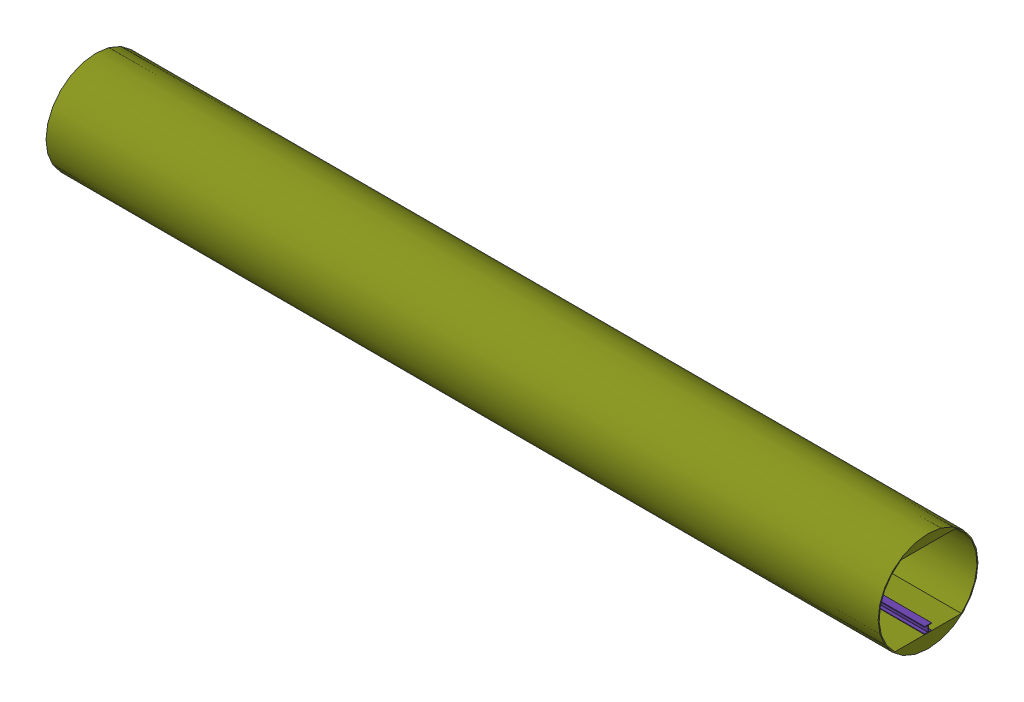
SolidWorks assembly full_vehicle_on_track, configuration Default. Lengths in mm.
Overall size (15240 1828.8 1828.8).
31 component instances, 17 part files, 5 mates.
Components (placement in the parent):
- full_vehicle-1: full_vehicle [Default] at (2562.0432 -2358.5258 -4406.3331) size (6096.03 1166.77 1555.25)
  - sledFrame_003_rw-1: sledFrame_003_rw [Default] at (-4891.4665 1903.7696 4433.3238) size (5588 50.8 1016)
  - drive_assembly-1: drive_assembly [Default] at (-3341.0425 1915.3862 4244.1915) x (0 0 1) z (-1 0 0) size (346.08 495.3 1111.25)
    - motor-1: motor [Default] at (4.9823 194.7584 300.6208) size (114.3 330.2 254)
    - drive_wheel-1: drive_wheel [Default] at (189.1323 143.9584 -16.8792) x (0 0 -1) z (1 0 0) size (304.8 304.8 101.6)
    - vertical_stability-1: vertical_stability [Default] at (189.1323 -124.9768 -16.8792) size (165.1 348.85 530.75)
    - drive_wheel-2: drive_wheel [Default] at (189.1323 143.9584 618.1208) x (0 0 1) z (-1 0 0) size (304.8 304.8 101.6)
    - vertical_stability-2: vertical_stability [Default] at (189.1323 -124.9768 618.1208) x (-1 0 0) z (0 0 -1) size (165.1 348.85 530.75)
    - Part1^drive_assembly-1: Part1^drive_assembly [Default] at (84.3573 143.9584 -16.8792) size (12.7 192.09 339.73) (virtual)
    - Part1^drive_assembly-2: Part1^drive_assembly [Default] at (281.2073 143.9584 -16.8792) size (12.7 192.09 339.73) (virtual)
    - Part1^drive_assembly-3: Part1^drive_assembly [Default] at (84.3573 143.9584 618.1208) size (12.7 192.09 339.73) (virtual)
    - Part1^drive_assembly-4: Part1^drive_assembly [Default] at (281.2073 143.9584 618.1208) size (12.7 192.09 339.73) (virtual)
  - battery_pack-1: battery_pack [Default] at (-3018.7283 2021.2446 4823.2138) x (0 0 -1) z (1 0 0) size (134.62 152.4 1325.88)
  - battery_pack-2: battery_pack [Default] at (-3018.7283 2021.2446 4043.4338) x (0 0 1) z (-1 0 0) size (134.62 152.4 1325.88)
  - Body_006_rw-1: Body_006_rw [Default] at (-5653.4665 1954.5696 4433.3238) x (1 0 0.000021) z (-0.000021 0 1) size (6096 981.34 1555.12)
  - radiator-1: radiator [Default] at (-3872.1683 2287.9446 3998.3488) x (-1 0 0) z (0 0 1) size (381 685.8 44.45)
  - horizontal_stability-1: horizontal_stability [Default] at (-2876.2243 1919.6446 4433.3238) x (0 0 -1) z (1 0 0) size (307.09 115.06 127)
  - horizontal_stability-2: horizontal_stability [Default] at (-4311.8611 1919.6446 4433.3238) x (0 0 -1) z (1 0 0) size (307.09 115.06 127)
  - friction_brake-1: friction_brake [Default] at (-4777.1665 1901.7122 4404.7488) x (0 0 -1) z (1 0 0) size (107.95 142.42 127)
  - friction_brake-2: friction_brake [Default] at (-4777.1665 1901.7122 4461.8988) x (0 0 1) z (-1 0 0) size (107.95 142.42 127)
  - friction_brake-3: friction_brake [Default] at (-2451.0383 1901.7122 4404.7488) x (0 0 -1) z (1 0 0) size (107.95 142.42 127)
  - friction_brake-4: friction_brake [Default] at (-2451.0383 1901.7122 4461.8988) x (0 0 1) z (-1 0 0) size (107.95 142.42 127)
  - air_tank-1: air_tank [Default] at (-3359.7769 2030.7696 4686.1159) x (0 0 -1) z (1 0 0) size (152.4 152.4 279.4)
  - compressor-1: compressor [Default] at (-2979.22 2008.5446 4702.3337) x (0 0 -1) z (1 0 0) size (127 127 254)
  - radiator-2: radiator [Default] at (-3872.1683 2287.9446 4868.2988) x (-1 0 0) z (0 0 1) size (381 685.8 44.45)
  - male95_scaled-1: male95_scaled [Default] at (-4390.3879 2202.234 4397.5196) x (-0.009816 -0.01136 0.999887) z (-0.756636 0.653836 0) size (328.47 766.25 480.34)
  - pressure_vessel-1: pressure_vessel [Default] at (-5056.735 1954.5696 4433.3238) x (0 0 -1) z (1 0 0) size (457.2 508 1117.6)
  - Seat assembly-3: Seat assembly [Default] at (-4400.9888 1860.8969 4286.9527) x (0 0 1) z (-1 0 0) size (311.15 341.17 561.02)
- test_track-1: test_track [Default] at (5757.7866 -4904.3333 -2803.8758) x (0 0 1) z (-1 0 0) size (1828.8 1828.8 15240)
  - tunnel-1: tunnel [Default] at (2830.8665 4983.259 8849.2099) size (1828.8 1828.8 15240)
  - rail_v2-1: rail_v2 [Default] at (2830.8665 4389.2521 4277.2099) size (127 127 15240)
Mates (geometry in assembly coordinates):
- Pod Parallel to Track: parallel: plane of full_vehicle-1 through (2562.0432 -2358.5258 -4406.3331) normal (0 1 0); plane of test_track-1 through (5757.7866 -5463.994 -2803.8758) normal (0 1 0)
- Pod Pointed in Direction of Motion: parallel: plane of full_vehicle-1 through (2562.0432 -2358.5258 -4406.3331) normal (0 0 1); plane of test_track-1 through (5757.7866 -5463.994 -2803.8758) normal (0 0 1)
- Pod Position Along Tube: coincident: line of full_vehicle-1/sledFrame_003_rw-1 through (-3091.4233 -407.1312 26.9908) axis (0 1 0); point of test_track-1/tunnel-1
- Pod Centered on Tube: coincident: plane of full_vehicle-1/sledFrame_003_rw-1 through (-2329.4233 -454.7562 26.9908) normal (0 0 1); plane of test_track-1/tunnel-1 through (-3091.4233 -480.7351 26.9908) normal (0 0 1)
- Drive Wheel Rolling on Rail: tangent anti-aligned: cylinder of full_vehicle-1/drive_assembly-1/drive_wheel-2 through (-1397.1201 -299.1812 -23.8092) axis (0 0 1) radius 152.4; plane of test_track-1/rail_v2-1 through (-6139.4233 -451.5812 -34.9852) normal (0 1 0)
